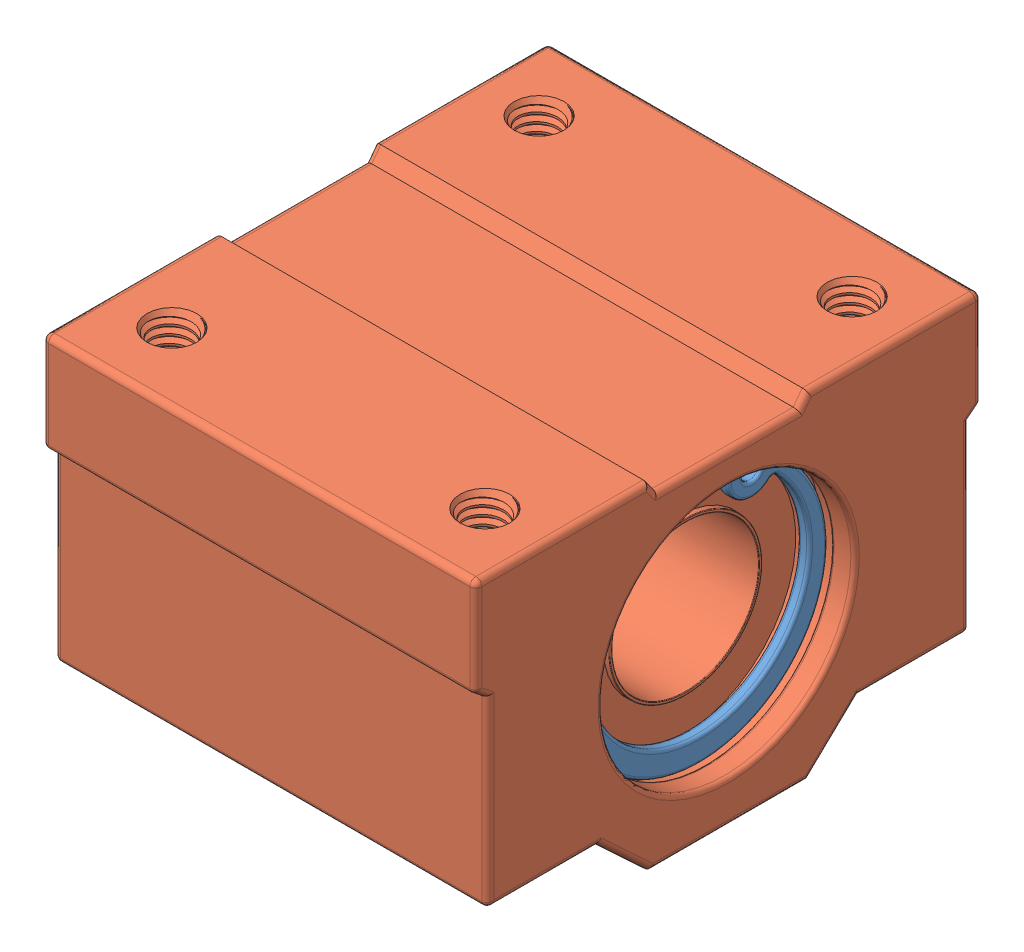
SolidWorks assembly PILLOW 12MM FINAL, configuration Valor predeterminado. Lengths in mm.
Overall size (36 28.21 42).
3 component instances, 2 part files, 0 mates.
Components (placement in the parent):
- CLAMP-1: CLAMP [Valor predeterminado] at (13.886 -11.8235 21.4636) x (0 0 1) z (-1 0 0) size (21.2 20.68 1.18)
- pillow 12mm M4-1: pillow 12mm M4 [Valor predeterminado] at (10.5245 -11.8137 21.45) size (36 28.21 42)
- CLAMP-2: CLAMP [Valor predeterminado] at (44.1964 -11.8301 21.4981) x (0 0 1) z (-1 0 0) size (21.2 20.68 1.18)
